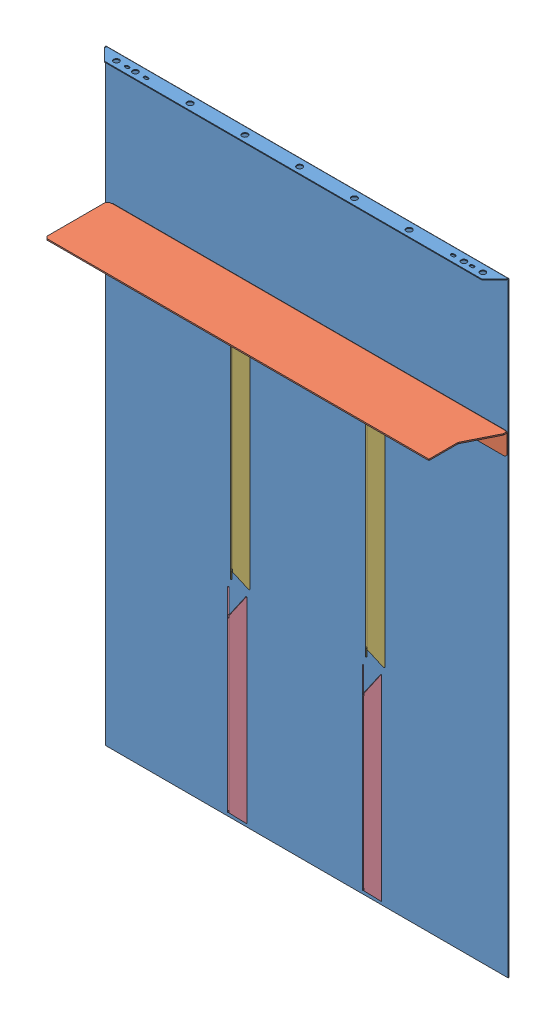
SolidWorks assembly 機體左板, configuration 預設. Lengths in mm.
Overall size (956 1468.3 173.55).
6 component instances, 4 part files, 12 mates.
Components (placement in the parent):
- LB-A54A-02-25-1: LB-A54A-02-25 [預設] at (-80501.2269 12822.4182 -1) size (956 1468.3 34.19)
- LB-A54A-02-9-1: LB-A54A-02-9 [預設] at (-520.391 339.3107 -46.78) x (1 0 0) z (0 -1 0) size (948 152.22 53.22)
- LB-A54A-02-23-1: LB-A54A-02-23 [預設] at (-186.4707 336.0907 45.7599) x (0 -1 0) z (0.707107 0 -0.707107) size (628.6 32.46 32.46)
- LB-A54A-02-23-2: LB-A54A-02-23 [預設] at (133.5293 336.0907 45.7599) x (0 -1 0) z (0.707107 0 -0.707107) size (628.6 32.46 32.46)
- LB-A54A-02-24-1: LB-A54A-02-24 [預設] at (-234.3113 -777.1798 45.7599) x (0 1 0) z (-0.707107 0 -0.707107) size (465.6 32.46 32.46)
- LB-A54A-02-24-2: LB-A54A-02-24 [預設] at (85.6887 -777.1798 45.7599) x (0 1 0) z (-0.707107 0 -0.707107) size (465.6 32.46 32.46)
Mates (geometry in assembly coordinates):
- 重合/共線/共點1: coincident anti-aligned: plane of LB-A54A-02-25-1 through (-528.391 -785.5893 1) normal (0 0 1); plane of LB-A54A-02-9-1 through (422.609 337.3407 1) normal (0 0 -1)
- 重合/共線/共點2: coincident: line of LB-A54A-02-25-1 through (-528.391 339.3107 -1) axis (1 0 0); plane of LB-A54A-02-9-1 through (422.609 339.3107 4.47) normal (0 1 0)
- 重合/共線/共點3: coincident: point of LB-A54A-02-25-1; plane of LB-A54A-02-9-1 through (427.609 291.0907 4) normal (1 0 0)
- 重合/共線/共點6: coincident: plane of LB-A54A-02-25-1 through (-528.391 -785.5893 1) normal (0 0 1); line of LB-A54A-02-23-1 through (-185.3252 286.0907 1) axis (0 -1 0)
- 重合/共線/共點7: coincident: plane of LB-A54A-02-25-1 through (-528.391 -785.5893 1) normal (0 0 1); line of LB-A54A-02-23-1 through (-227.9779 -291.9093 1) axis (0 1 0)
- 重合/共線/共點8: coincident: line of LB-A54A-02-25-1 through (-233.2306 286.3107 -1) axis (0 -1 0); plane of LB-A54A-02-23-1 through (-208.5678 -249.749 23.6628) normal (-0.707107 0 0.707107)
- 重合/共線/共點9: coincident anti-aligned: plane of LB-A54A-02-9-1 through (-510.391 286.0907 4) normal (0 -1 0); plane of LB-A54A-02-23-1 through (-227.9779 286.0907 1) normal (0 1 0)
- 重合/共線/共點10: coincident: plane of LB-A54A-02-25-1 through (-528.391 -785.5893 1) normal (0 0 1); line of LB-A54A-02-24-1 through (-192.8041 -312.1798 1) axis (0 -1 0)
- 重合/共線/共點11: coincident: plane of LB-A54A-02-25-1 through (-528.391 -785.5893 1) normal (0 0 1); line of LB-A54A-02-24-1 through (-235.4568 -777.1798 1) axis (0 1 0)
- 重合/共線/共點12: coincident: line of LB-A54A-02-25-1 through (-187.5515 -313.8893 -1) axis (0 -1 0); plane of LB-A54A-02-24-1 through (-212.2142 -354.34 23.6628) normal (0.707107 0 0.707107)
- 重合/共線/共點14: coincident: unknown of LB-A54A-02-25-1; plane of LB-A54A-02-24-1 through (-194.0769 -311.5798 2.2728) normal (0.223607 0.948683 -0.223607)
- 局部直線複製2: unknown: line of LB-A54A-02-25-1 through (-528.391 -299.5553 -1) axis (1 0 0)
